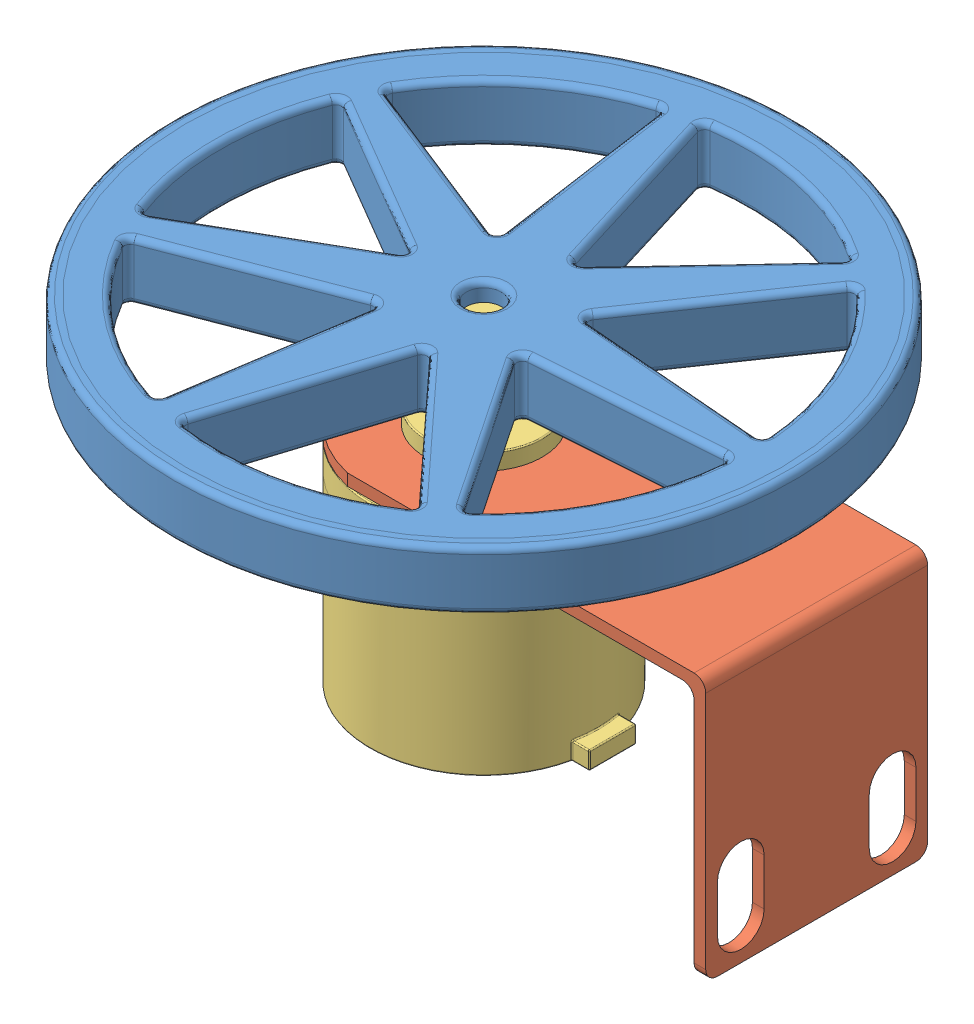
SolidWorks assembly Wheel_Assembly, configuration Default. Lengths in mm.
Overall size (110 64 106).
3 component instances, 3 part files, 5 mates.
Components (placement in the parent):
- 106_alum_wheel-1: 106_alum_wheel [Default] at (35.9984 80.6835 65.9188) size (106 18 106)
- encoder_bracket-1: encoder_bracket [Default] at (31.6109 71.6835 46.9188) x (1 0 0) z (0 0 -1) size (76.5 45 38)
- encoder-1: encoder [Default] at (35.9984 33.1835 65.9188) x (0 0 -1) z (1 0 0) size (39 54.35 41.59)
Mates (geometry in assembly coordinates):
- Concentric1: concentric anti-aligned: cylinder of encoder_bracket-1 through (35.9984 69.6835 65.9188) axis (0 1 0) radius 10; cylinder of encoder-1 through (35.9984 74.5335 65.9188) axis (0 -1 0) radius 10
- Coincident1: coincident anti-aligned: plane of encoder_bracket-1 through (31.6109 69.6835 46.9188) normal (0 -1 0); plane of encoder-1 through (35.9984 69.6835 65.9188) normal (0 1 0)
- Concentric2: concentric anti-aligned: circle of 106_alum_wheel-1; cylinder of encoder-1 through (35.9984 87.5335 65.9188) axis (0 -1 0) radius 3
- Distance1: distance = 1 mm anti-aligned: plane of encoder_bracket-1 through (31.6109 71.6835 46.9188) normal (0 1 0); plane of 106_alum_wheel-1 through (35.9984 72.6835 65.9188) normal (0 -1 0)
- Parallel1: parallel anti-aligned: plane of encoder_bracket-1 through (90.9984 26.6835 46.9188) normal (-1 0 0); plane of encoder-1 through (58.0838 36.1835 69.9188) normal (1 0 0)
